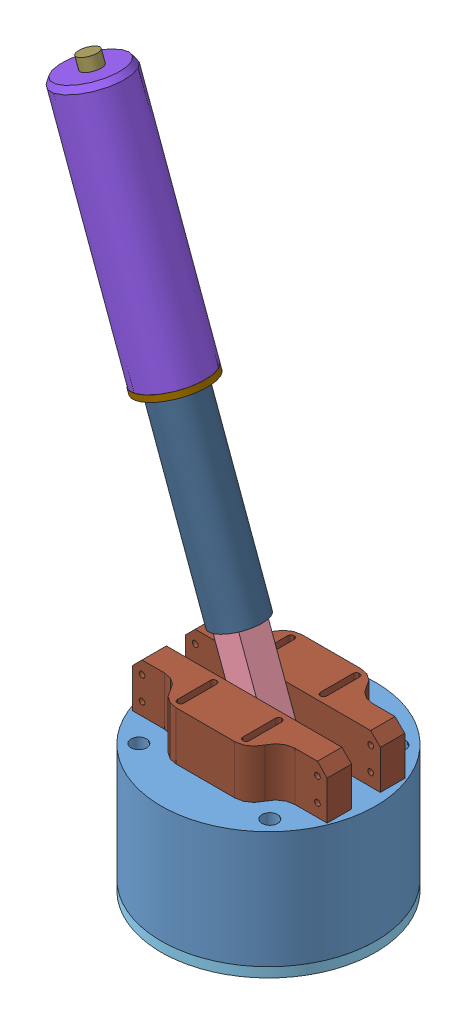
SolidWorks assembly collective, configuration По умолчанию. Lengths in mm.
Overall size (168.45 348.4 110).
14 component instances, 12 part files, 36 mates.
Components (placement in the parent):
- case_collective-1: case_collective [По умолчанию] at origin size (110 60 110)
- collective_frame_4,5x42mm-1: collective_frame_4,5x42mm [По умолчанию] at (25.25 42 0) x (0 0 1) z (0 -1 0) size (56 48 30)
- 608_bearing_v1-1: 608_bearing_v1 [По умолчанию] at (9.25 42 10.5) x (1 0 0) z (0 -1 0) size (22 7.15 22)
- 608_bearing_v1-2: 608_bearing_v1 [По умолчанию] at (9.25 42 -10.5) x (1 0 0) z (0 1 0) size (22 7.15 22)
- collective_connector-1: collective_connector [По умолчанию] at (-2.16 73.0712 -7.3) x (0 0 1) z (0.344713 -0.938708 0) size (49.8 14.8 74)
- collective_case_bottom_cover-1: collective_case_bottom_cover [По умолчанию] at (0 -5 0) size (110 30 110)
- aluminium_square_pipe_10x250-1: aluminium_square_pipe_10x250 [По умолчанию] at (7.492 46.7874 0.1) x (0.938708 0.344713 0) z (0 0 1) size (10 250 10)
- throttle_resistor_mount_v2-1: throttle_resistor_mount_v2 [По умолчанию] at (-88.2784 313.0967 0) x (0 0 1) z (0.938708 0.344713 0) size (20 58 22)
- throttle-1: throttle [По умолчанию] at (-48.7902 199.7623 0) x (-0.445982 -0.163774 -0.879931) z (-0.344713 0.938708 0) size (35 35 123)
- throttle_rear_mount-1: throttle_rear_mount [По умолчанию] at (-50.5138 204.4559 0) x (-0.938708 -0.344713 0) z (0 0 1) size (35 13 35)
- collective_lever_decorative_cover-1: collective_lever_decorative_cover [По умолчанию] at (-15.0083 107.769 0) x (0.938708 0.344713 0) z (0 0 1) size (25 95 25)
- tensioner-3: tensioner [По умолчанию] at (0.15 60 20) x (0 0 -1) z (1 0 0) size (25 25 100)
- tensioner-4: tensioner [По умолчанию] at (0.15 60 -19.8) x (0 0 1) z (-1 0 0) size (25 25 100)
- throttle_handle_wedge-1: throttle_handle_wedge [По умолчанию] at (-93.0265 320.9408 -0.4345) x (-0.463721 -0.170288 0.869462) z (0.816171 0.299715 0.493999) size (10 9 10)
Mates (geometry in assembly coordinates):
- Концентричный2: concentric aligned: cylinder of case_collective-1 through (-16.75 0 -20.5) axis (0 1 0) radius 1.5; cylinder of collective_frame_4,5x42mm-1 through (-16.75 27 -20.5) axis (0 1 0) radius 1.5
- Концентричный4: concentric aligned: cylinder of case_collective-1 through (-16.75 0 20.5) axis (0 1 0) radius 1.5; cylinder of collective_frame_4,5x42mm-1 through (-16.75 27 20.5) axis (0 1 0) radius 1.5
- Совпадение1: coincident anti-aligned: plane of case_collective-1 through (22.5 57 22.5) normal (0 -1 0); plane of collective_frame_4,5x42mm-1 through (-16.75 57 17.5) normal (0 1 0)
- Концентричный5: concentric anti-aligned: cylinder of collective_frame_4,5x42mm-1 through (9.25 42 -10.5) axis (0 0 -1) radius 11.1; cylinder of 608_bearing_v1-2 through (9.25 42 -13.975) axis (0 0 1) radius 11
- Совпадение2: coincident anti-aligned: plane of collective_frame_4,5x42mm-1 through (9.25 42 -10.5) normal (0 0 -1); plane of 608_bearing_v1-2 through (9.25 42 -10.5) normal (0 0 1)
- Концентричный6: concentric anti-aligned: cylinder of collective_frame_4,5x42mm-1 through (9.25 42 10.5) axis (0 0 1) radius 11.1; cylinder of 608_bearing_v1-1 through (9.25 42 13.975) axis (0 0 -1) radius 11
- Совпадение3: coincident anti-aligned: plane of collective_frame_4,5x42mm-1 through (9.25 42 10.5) normal (0 0 1); plane of 608_bearing_v1-1 through (9.25 42 10.5) normal (0 0 -1)
- Концентричный7: concentric aligned: cylinder of 608_bearing_v1-2 through (9.25 42 -13.975) axis (0 0 1) radius 4; cylinder of collective_connector-1 through (9.25 42 -32.3) axis (0 0 1) radius 3.9
- Совпадение4: coincident anti-aligned: plane of 608_bearing_v1-2 through (9.25 42 -10.4) normal (0 0 1); plane of collective_connector-1 through (-2.16 73.0712 -10.4) normal (0 0 -1)
- Концентричный8: concentric anti-aligned: cylinder of case_collective-1 through (-33.5917 0 -32.8724) axis (0 1 0) radius 4; cylinder of collective_case_bottom_cover-1 through (-33.5917 5 -32.8724) axis (0 -1 0) radius 4.1
- Концентричный9: concentric anti-aligned: cylinder of case_collective-1 through (-33.5917 0 32.8724) axis (0 1 0) radius 4; cylinder of collective_case_bottom_cover-1 through (-33.5917 5 32.8724) axis (0 -1 0) radius 4.1
- Совпадение5: coincident anti-aligned: plane of case_collective-1 through (0 0 0) normal (0 -1 0); plane of collective_case_bottom_cover-1 through (0 0 0) normal (0 1 0)
- Совпадение6: coincident anti-aligned: plane of collective_connector-1 through (2.7984 45.0638 -4.9) normal (0.938708 0.344713 0); plane of aluminium_square_pipe_10x250-1 through (-83.3799 279.7408 5.1) normal (-0.938708 -0.344713 0)
- Совпадение7: coincident anti-aligned: plane of collective_connector-1 through (12.1855 48.511 -4.9) normal (0 0 1); plane of aluminium_square_pipe_10x250-1 through (-73.9928 283.188 -4.9) normal (0 0 -1)
- Совпадение8: coincident anti-aligned: plane of collective_connector-1 through (7.492 46.7874 -7.3) normal (-0.344713 0.938708 0); plane of aluminium_square_pipe_10x250-1 through (7.492 46.7874 0.1) normal (0.344713 -0.938708 0)
- Совпадение9: coincident anti-aligned: plane of aluminium_square_pipe_10x250-1 through (-73.9928 283.188 5.1) normal (0.938708 0.344713 0); plane of throttle_resistor_mount_v2-1 through (-73.9928 283.188 -5.1) normal (-0.938708 -0.344713 0)
- Совпадение10: coincident anti-aligned: plane of aluminium_square_pipe_10x250-1 through (-73.9928 283.188 5.1) normal (0 0 1); plane of throttle_resistor_mount_v2-1 through (-73.9928 283.188 5.1) normal (0 0 -1)
- Совпадение11: coincident anti-aligned: plane of aluminium_square_pipe_10x250-1 through (-78.6864 281.4644 0.1) normal (-0.344713 0.938708 0); plane of throttle_resistor_mount_v2-1 through (-76.9028 282.1194 0) normal (0.344713 -0.938708 0)
- Концентричный10: concentric anti-aligned: cylinder of throttle_resistor_mount_v2-1 through (-89.1216 309.5912 0) axis (-0.344713 0.938708 0) radius 3.5; cylinder of throttle-1 through (-91.1899 315.2234 0) axis (0.344713 -0.938708 0) radius 3
- Концентричный11: concentric anti-aligned: cylinder of throttle-1 through (-90.1558 312.4073 0) axis (0.344713 -0.938708 0) radius 15.1; cylinder of throttle_rear_mount-1 through (-48.7902 199.7623 0) axis (-0.344713 0.938708 0) radius 14.8
- Совпадение14: coincident anti-aligned: plane of aluminium_square_pipe_10x250-1 through (-73.9928 283.188 5.1) normal (0 0 1); plane of collective_lever_decorative_cover-1 through (-42.9686 198.7043 5.1) normal (0 0 -1)
- Совпадение15: coincident anti-aligned: plane of aluminium_square_pipe_10x250-1 through (-73.9928 283.188 5.1) normal (0.938708 0.344713 0); plane of collective_lever_decorative_cover-1 through (-42.9686 198.7043 5.1) normal (-0.938708 -0.344713 0)
- Совпадение16: coincident anti-aligned: plane of throttle_rear_mount-1 through (-47.756 196.9462 0) normal (0.344713 -0.938708 0); plane of collective_lever_decorative_cover-1 through (-47.756 196.9462 0) normal (-0.344713 0.938708 0)
- Совпадение19: coincident anti-aligned: plane of case_collective-1 through (0 60 0) normal (0 1 0); plane of tensioner-4 through (0.15 60 -19.8) normal (0 -1 0)
- Касательность3: tangent anti-aligned: cylinder of case_collective-1 through (-16.75 0 -20.5) axis (0 1 0) radius 1.5; plane of tensioner-4 through (-18.25 85 -9.8) normal (1 0 0)
- Касательность5: tangent anti-aligned: cylinder of case_collective-1 through (16.75 0 -20.5) axis (0 1 0) radius 1.5; plane of tensioner-4 through (15.25 85 -9.8) normal (1 0 0)
- Совпадение20: coincident anti-aligned: plane of case_collective-1 through (0 60 0) normal (0 1 0); plane of tensioner-3 through (0.15 60 20) normal (0 -1 0)
- Касательность6: tangent anti-aligned: cylinder of case_collective-1 through (-16.75 0 20.5) axis (0 1 0) radius 1.5; plane of tensioner-3 through (-18.25 85 10) normal (1 0 0)
- Совпадение21: coincident anti-aligned: plane of collective_connector-1 through (-2.16 73.0712 7.5) normal (0 0 1); plane of tensioner-3 through (50.15 85 7.5) normal (0 0 -1)
- Совпадение22: coincident anti-aligned: plane of collective_connector-1 through (-2.16 73.0712 -7.3) normal (0 0 -1); plane of tensioner-4 through (-49.85 85 -7.3) normal (0 0 1)
- Концентричный16: concentric aligned: cylinder of throttle-1 through (-91.1899 315.2234 0) axis (0.344713 -0.938708 0) radius 3; cylinder of throttle_handle_wedge-1 through (-92.5688 318.9783 0) axis (0.344713 -0.938708 0) radius 3.2
- Совпадение23: coincident anti-aligned: plane of collective_connector-1 through (-7.968 110.3543 7.5) normal (-0.344713 0.938708 0); plane of collective_lever_decorative_cover-1 through (-15.0083 107.769 0) normal (0.344713 -0.938708 0)
- Параллельность1: parallel anti-aligned: plane of aluminium_square_pipe_10x250-1 through (-83.3799 279.7408 5.1) normal (-0.938708 -0.344713 0); plane of throttle_rear_mount-1 through (-55.3012 202.6978 5.1) normal (0.938708 0.344713 0)
- Угол1: planar angle = 0.174533 rad anti-aligned: plane of throttle-1 through (-68.157 213.9563 7.174) normal (-0.445982 -0.163774 -0.879931); plane of throttle_rear_mount-1 through (-65.4225 204.3075 4.6633) normal (0.295774 0.108614 0.949063)
- Совпадение27: coincident anti-aligned: plane of throttle-1 through (-48.7902 199.7623 0) normal (0.344713 -0.938708 0); plane of throttle_rear_mount-1 through (-48.7902 199.7623 0) normal (-0.344713 0.938708 0)
- Совпадение28: coincident anti-aligned: plane of throttle-1 through (-91.1899 315.2234 0) normal (-0.344713 0.938708 0); plane of throttle_handle_wedge-1 through (-90.9582 315.3085 -0.4345) normal (0.344713 -0.938708 0)
